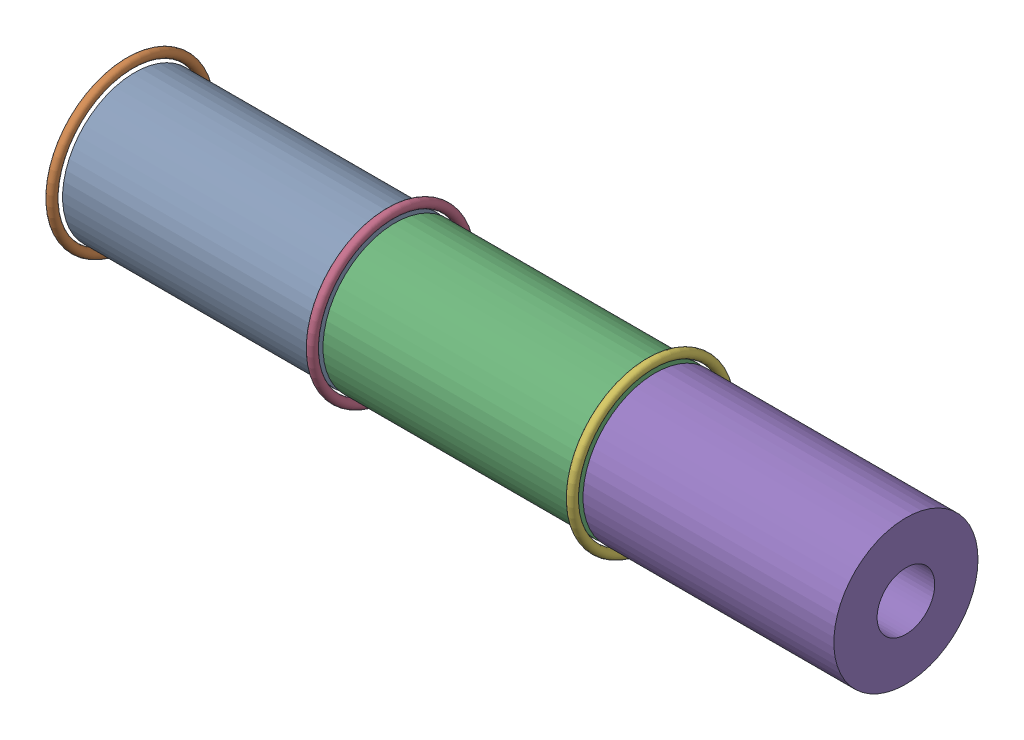
SolidWorks assembly 00_submontagem_graos_tres, configuration Valor predeterminado. Lengths in mm.
Overall size (270.62 57.15 57.15).
9 component instances, 2 part files, 4 mates.
Components (placement in the parent):
- 00_submontagem_graos-1: 00_submontagem_graos [Valor predeterminado] at (7.4457 -6.08 28.575) size (90.11 57.15 57.15)
  - 04_grao_propelente-1: 04_grao_propelente [Valor predeterminado] at (-67.3104 10.7905 25) size (87 50 50)
  - 06_anel_de_vedacao-1: 06_anel_de_vedacao [Valor predeterminado] at (-68.9177 10.7905 25) size (3 57.15 57.15)
- 00_submontagem_graos-2: 00_submontagem_graos [Valor predeterminado] at (97.7681 -6.08 28.575) size (90.11 57.15 57.15)
  - 04_grao_propelente-1: 04_grao_propelente [Valor predeterminado] at (-67.3104 10.7905 25) size (87 50 50)
  - 06_anel_de_vedacao-1: 06_anel_de_vedacao [Valor predeterminado] at (-68.9177 10.7905 25) size (3 57.15 57.15)
- 00_submontagem_graos-3: 00_submontagem_graos [Valor predeterminado] at (187.9623 -6.08 28.575) size (90.11 57.15 57.15)
  - 04_grao_propelente-1: 04_grao_propelente [Valor predeterminado] at (-67.3104 10.7905 25) size (87 50 50)
  - 06_anel_de_vedacao-1: 06_anel_de_vedacao [Valor predeterminado] at (-68.9177 10.7905 25) size (3 57.15 57.15)
Mates (geometry in assembly coordinates):
- Coincidente1: coincident aligned: plane of 00_submontagem_graos-1 through (7.4457 -6.08 28.575) normal (0 0 1); plane of 00_submontagem_graos-2 through (97.7681 -6.08 28.575) normal (0 0 1)
- Coincidente2: coincident aligned: plane of 00_submontagem_graos-1 through (7.4457 -6.08 28.575) normal (0 1 0); plane of 00_submontagem_graos-2 through (97.7681 -6.08 28.575) normal (0 1 0)
- Coincidente3: coincident aligned: plane of 00_submontagem_graos-2 through (97.7681 -6.08 28.575) normal (0 1 0); plane of 00_submontagem_graos-3 through (187.9623 -6.08 28.575) normal (0 1 0)
- Coincidente4: coincident aligned: plane of 00_submontagem_graos-2 through (97.7681 -6.08 28.575) normal (0 0 1); plane of 00_submontagem_graos-3 through (187.9623 -6.08 28.575) normal (0 0 1)
